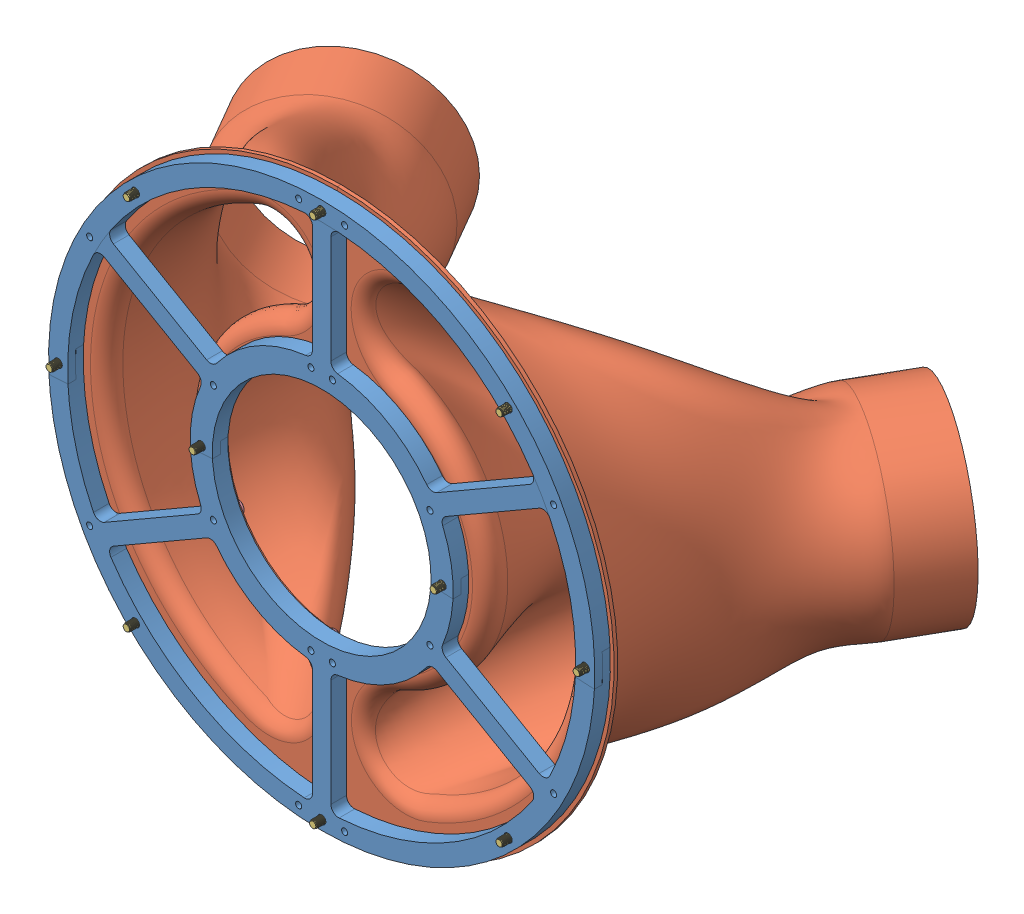
SolidWorks assembly IDS WSC Beampipe Support Assy, configuration Default. Lengths in mm.
Overall size (306.73 225 155.21).
30 component instances, 4 part files, 17 mates.
Components (placement in the parent):
- IDS WSC West Beampipe Support-1: IDS WSC West Beampipe Support [Default] at origin size (222 116.81 6.35)
- IDS WSC West Beampipe Support-2: IDS WSC West Beampipe Support [Default] x (1 0 0) z (0 0 -1) size (222 116.81 6.35)
- IDS WSC Inlet Manifold-1: IDS WSC Inlet Manifold [Default] at (0 0 -4.675) x (-1 0 0) z (0 0 -1) size (153.36 225 145.2)
- IDS WSC Inlet Manifold-3: IDS WSC Inlet Manifold [Default] at (0 0 -4.675) x (1 0 0) z (0 0 -1) size (153.36 225 145.2)
- M3x10 screw 92855A310-1: M3x10 screw 92855A310 [92855A310] at (0 107.125 -3.175) x (-1 0 0) z (0 0 -1) size (5.5 5.5 12.13)
- M3x10 screw 92855A310-2: M3x10 screw 92855A310 [92855A310] at (49 0 -3.175) x (-1 0 0) z (0 0 -1) size (5.5 5.5 12.13)
- M3 x 6 screw 92855A307-1: M3 x 6 screw 92855A307 [92855A307] at (4.3578 49.8097 -4.675) x (-1 0 0) z (0 0 -1) size (5.5 5.5 8.13)
- M3 x 6 screw 92855A307-2: M3 x 6 screw 92855A307 [92855A307] at (9.3366 106.7174 -4.675) x (-1 0 0) z (0 0 -1) size (5.5 5.5 8.13)
- M3x10 screw 92855A310-3: M3x10 screw 92855A310 [92855A310] at (75.7488 75.7488 -3.175) x (-0.707107 0.707107 0) z (0 0 -1) size (5.5 5.5 12.13)
- M3x10 screw 92855A310-4: M3x10 screw 92855A310 [92855A310] at (107.125 0 -3.175) x (0 1 0) z (0 0 -1) size (5.5 5.5 12.13)
- M3x10 screw 92855A310-5: M3x10 screw 92855A310 [92855A310] at (75.7488 -75.7488 -3.175) x (0.707107 0.707107 0) z (0 0 -1) size (5.5 5.5 12.13)
- M3x10 screw 92855A310-6: M3x10 screw 92855A310 [92855A310] at (0 -107.125 -3.175) x (1 0 0) z (0 0 -1) size (5.5 5.5 12.13)
- M3x10 screw 92855A310-7: M3x10 screw 92855A310 [92855A310] at (-75.7488 -75.7488 -3.175) x (0.707107 -0.707107 0) z (0 0 -1) size (5.5 5.5 12.13)
- M3x10 screw 92855A310-8: M3x10 screw 92855A310 [92855A310] at (-107.125 0 -3.175) x (0 -1 0) z (0 0 -1) size (5.5 5.5 12.13)
- M3x10 screw 92855A310-9: M3x10 screw 92855A310 [92855A310] at (-75.7488 75.7488 -3.175) x (-0.707107 -0.707107 0) z (0 0 -1) size (5.5 5.5 12.13)
- M3x10 screw 92855A310-10: M3x10 screw 92855A310 [92855A310] at (-49 0 -3.175) x (1 0 0) z (0 0 -1) size (5.5 5.5 12.13)
- M3 x 6 screw 92855A307-3: M3 x 6 screw 92855A307 [92855A307] at (44.0101 23.73 -4.675) x (-0.549509 0.835488 0) z (0 0 -1) size (5.5 5.5 8.13)
- M3 x 6 screw 92855A307-4: M3 x 6 screw 92855A307 [92855A307] at (44.0101 -23.73 -4.675) x (0.39608 0.918216 0) z (0 0 -1) size (5.5 5.5 8.13)
- M3 x 6 screw 92855A307-5: M3 x 6 screw 92855A307 [92855A307] at (4.3578 -49.8097 -4.675) x (0.984808 0.173648 0) z (0 0 -1) size (5.5 5.5 8.13)
- M3 x 6 screw 92855A307-6: M3 x 6 screw 92855A307 [92855A307] at (94.2916 50.8416 -4.675) x (-0.549509 0.835488 0) z (0 0 -1) size (5.5 5.5 8.13)
- M3 x 6 screw 92855A307-7: M3 x 6 screw 92855A307 [92855A307] at (94.2916 -50.8416 -4.675) x (0.39608 0.918216 0) z (0 0 -1) size (5.5 5.5 8.13)
- M3 x 6 screw 92855A307-8: M3 x 6 screw 92855A307 [92855A307] at (9.3366 -106.7174 -4.675) x (0.984808 0.173648 0) z (0 0 -1) size (5.5 5.5 8.13)
- M3 x 6 screw 92855A307-9: M3 x 6 screw 92855A307 [92855A307] at (-9.3366 106.7174 -4.675) x (-1 0 0) z (0 0 -1) size (5.5 5.5 8.13)
- M3 x 6 screw 92855A307-10: M3 x 6 screw 92855A307 [92855A307] at (-4.3578 49.8097 -4.675) x (-1 0 0) z (0 0 -1) size (5.5 5.5 8.13)
- M3 x 6 screw 92855A307-11: M3 x 6 screw 92855A307 [92855A307] at (-44.0101 23.73 -4.675) x (-0.549509 -0.835488 0) z (0 0 -1) size (5.5 5.5 8.13)
- M3 x 6 screw 92855A307-12: M3 x 6 screw 92855A307 [92855A307] at (-44.0101 -23.73 -4.675) x (0.39608 -0.918216 0) z (0 0 -1) size (5.5 5.5 8.13)
- M3 x 6 screw 92855A307-13: M3 x 6 screw 92855A307 [92855A307] at (-4.3578 -49.8097 -4.675) x (0.984808 -0.173648 0) z (0 0 -1) size (5.5 5.5 8.13)
- M3 x 6 screw 92855A307-14: M3 x 6 screw 92855A307 [92855A307] at (-94.2916 50.8416 -4.675) x (-0.549509 -0.835488 0) z (0 0 -1) size (5.5 5.5 8.13)
- M3 x 6 screw 92855A307-15: M3 x 6 screw 92855A307 [92855A307] at (-94.2916 -50.8416 -4.675) x (0.39608 -0.918216 0) z (0 0 -1) size (5.5 5.5 8.13)
- M3 x 6 screw 92855A307-16: M3 x 6 screw 92855A307 [92855A307] at (-9.3366 -106.7174 -4.675) x (0.984808 -0.173648 0) z (0 0 -1) size (5.5 5.5 8.13)
Mates (geometry in assembly coordinates):
- Coincident1: coincident anti-aligned: plane of IDS WSC West Beampipe Support-1 through (0 0 0) normal (0 1 0); plane of IDS WSC West Beampipe Support-2 through (0 0 0) normal (0 -1 0)
- Coincident2: coincident anti-aligned: plane of IDS WSC West Beampipe Support-1 through (0 0 0) normal (0 0 1); plane of IDS WSC West Beampipe Support-2 through (0 0 0) normal (0 0 -1)
- Coincident3: coincident aligned: plane of IDS WSC West Beampipe Support-1 through (0 0 0) normal (1 0 0); plane of IDS WSC West Beampipe Support-2
- Coincident4: coincident anti-aligned: plane of IDS WSC West Beampipe Support-1 through (0 -244.3414 -3.175) normal (0 0 -1); plane of IDS WSC Inlet Manifold-1 through (0 0 -3.175) normal (0 0 1)
- Coincident5: coincident anti-aligned: plane of IDS WSC Inlet Manifold-1 through (0 0 -4.675) normal (-1 0 0); plane of assembly through (0 0 0) normal (1 0 0)
- Coincident6: coincident aligned: plane of IDS WSC Inlet Manifold-1; plane of assembly through (0 0 0) normal (0 1 0)
- Coincident7: coincident aligned: plane of assembly through (0 0 0) normal (1 0 0); plane of IDS WSC Inlet Manifold-3
- Coincident8: coincident anti-aligned: plane of IDS WSC Inlet Manifold-3 through (0 0 -4.675) normal (0 -1 0); plane of assembly through (0 0 0) normal (0 1 0)
- Coincident9: coincident anti-aligned: plane of IDS WSC West Beampipe Support-1 through (0 -244.3414 -3.175) normal (0 0 -1); plane of IDS WSC Inlet Manifold-3 through (0 0 -3.175) normal (0 0 1)
- Coincident395: coincident anti-aligned: plane of IDS WSC West Beampipe Support-1 through (0 -244.3414 -3.175) normal (0 0 -1); plane of M3x10 screw 92855A310-1 through (0 107.125 -3.175) normal (0 0 1)
- Concentric282: concentric aligned: cylinder of IDS WSC West Beampipe Support-1 through (0 107.125 3.175) axis (0 0 1) radius 1.7; cylinder of M3x10 screw 92855A310-1 through (0 107.125 -5.175) axis (0 0 1) radius 2.75
- Concentric283: concentric anti-aligned: cylinder of IDS WSC West Beampipe Support-2 through (49 0 -3.175) axis (0 0 -1) radius 1.6; cylinder of M3x10 screw 92855A310-2 through (49 0 -5.175) axis (0 0 1) radius 2.75
- Coincident396: coincident anti-aligned: plane of IDS WSC West Beampipe Support-2 through (0 244.3414 -3.175) normal (0 0 -1); plane of M3x10 screw 92855A310-2 through (49 0 -3.175) normal (0 0 1)
- Concentric284: concentric anti-aligned: cylinder of IDS WSC West Beampipe Support-1 through (4.3578 49.8097 -3.175) axis (0 0 -1) radius 1.25; cylinder of M3 x 6 screw 92855A307-1 through (4.3578 49.8097 -6.675) axis (0 0 1) radius 2.75
- Coincident397: coincident anti-aligned: plane of IDS WSC Inlet Manifold-1 through (0 0 -4.675) normal (0 0 -1); plane of M3 x 6 screw 92855A307-1 through (4.3578 49.8097 -4.675) normal (0 0 1)
- Concentric285: concentric anti-aligned: cylinder of IDS WSC West Beampipe Support-1 through (9.3366 106.7174 -3.175) axis (0 0 -1) radius 1.25; cylinder of M3 x 6 screw 92855A307-2 through (9.3366 106.7174 -6.675) axis (0 0 1) radius 2.75
- Coincident398: coincident anti-aligned: plane of IDS WSC Inlet Manifold-1 through (0 0 -4.675) normal (0 0 -1); plane of M3 x 6 screw 92855A307-2 through (9.3366 106.7174 -4.675) normal (0 0 1)
